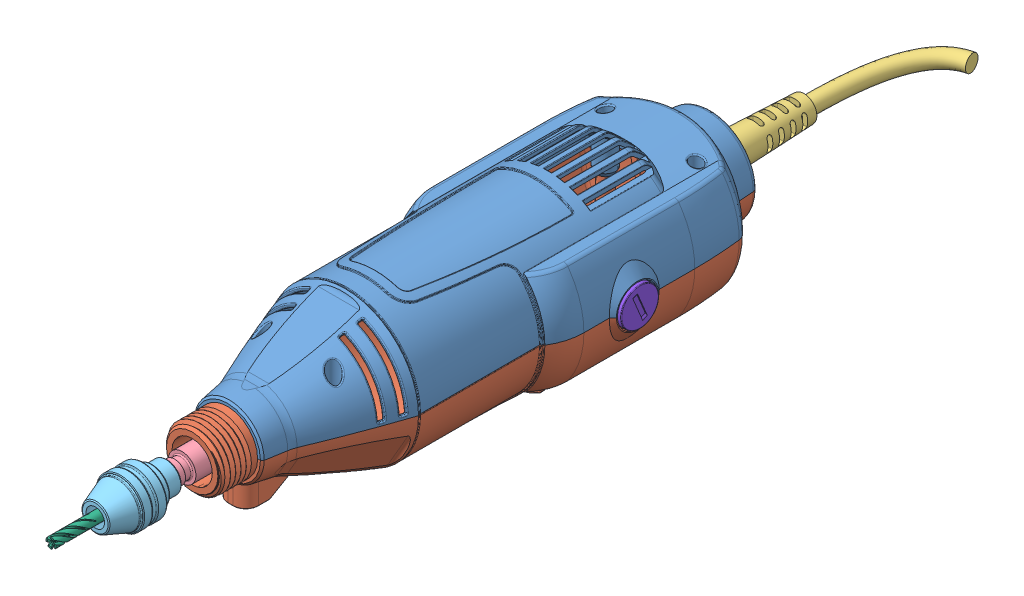
SolidWorks assembly Dremel Assembly, configuration Default. Lengths in mm.
Overall size (56.71 52.89 278.43).
9 component instances, 8 part files, 15 mates.
Components (placement in the parent):
- Dremel Left Half-1: Dremel Left Half [Default] at origin size (55.12 24.36 152.4)
- Dremel Right Half-1: Dremel Right Half [Default] x (-1 0 0) z (0 0 1) size (55.12 36.04 163.96)
- Dremel Chord-1: Dremel Chord [Default] at (0 0 -144.4625) x (1 0 0) z (0 1 0) size (22.66 78.4 16.21)
- Dremel Chuck Mount-1: Dremel Chuck Mount [Default] at (0 0 -7.9375) x (0.325874 -0.945413 0) z (-0.945413 -0.325874 0) size (8.71 38.1 8.71)
- Dremel Chuck-1: Dremel Chuck [Default] at (0 0 19.0627) x (0.99596 -0.0898 0) z (-0.0898 -0.99596 0) size (15.24 22.56 15.24)
- End Mill for Dremel-1: End Mill for Dremel [Default] at (0 0 30.1625) x (-0.564493 -0.825438 0) z (-0.825438 0.564493 0) size (5.5 25.4 5.5)
- Dremel Speed Lever-1: Dremel Speed Lever [Default] at (0 0 -93.09) x (-0.965324 -0.261055 0) z (0 0 1) size (27.22 10.71 7.94)
- Dremel Motor Adjust-1: Dremel Motor Adjust [Default] at (-22.0028 0 -101.6) x (0 0.384439 -0.92315) z (1 0 0) size (11.91 11.91 6.35)
- Dremel Motor Adjust-2: Dremel Motor Adjust [Default] at (22.0028 0 -101.6) x (0 -0.384439 0.92315) z (-1 0 0) size (11.91 11.91 6.35)
Mates (geometry in assembly coordinates):
- Coincident1: coincident anti-aligned: plane of Dremel Left Half-1 through (93.8758 0 -66.675) normal (0 -1 0); plane of Dremel Right Half-1 through (-93.8758 0 -66.675) normal (0 1 0)
- Coincident2: coincident anti-aligned: plane of Dremel Left Half-1 through (0 0 0) normal (1 0 0); plane of Dremel Right Half-1
- Coincident3: coincident aligned: plane of Dremel Left Half-1 through (0 0 0) normal (0 0 1); plane of Dremel Right Half-1 through (0 0 0) normal (0 0 1)
- Concentric1: concentric aligned: cylinder of Dremel Left Half-1 through (0 0 -152.4) axis (0 0 1) radius 6.35; cylinder of Dremel Chord-1 through (0 0 -144.4625) axis (0 0 1) radius 7.1437
- Coincident4: coincident anti-aligned: plane of Dremel Right Half-1 through (0 0 -152.4) normal (0 0 -1); plane of Dremel Chord-1 through (5.9531 0 -152.4) normal (0 0 1)
- Concentric2: concentric anti-aligned: cylinder of Dremel Right Half-1 through (0 0 -152.4) axis (0 0 1) radius 6.35; cylinder of Dremel Chuck Mount-1 through (0 0 -7.9375) axis (0 0 -1) radius 4.3561
- Distance1: distance = 19.05 mm aligned: plane of Dremel Chuck Mount-1 through (1.1381 -3.3019 30.1625) normal (0 0 1); plane of Dremel Right Half-1 through (-8.1085 0 11.1125) normal (0 0 1)
- Concentric4: concentric aligned: cylinder of Dremel Chuck Mount-1 through (0 0 -7.9375) axis (0 0 -1) radius 3.4925; cylinder of Dremel Chuck-1 through (0 0 19.0627) axis (0 0 -1) radius 3.3782
- Distance2: distance = 12.7 mm anti-aligned: plane of Dremel Right Half-1 through (-8.1085 0 11.1125) normal (0 0 1); plane of Dremel Chuck-1 through (5.7552 -0.5189 23.8125) normal (0 0 -1)
- Concentric5: concentric aligned: cone of Dremel Chuck-1 through (0 0 41.6179) axis (0 0 1); cylinder of End Mill for Dremel-1 through (0 0 55.5625) axis (0 0 1) radius 1.5875
- Coincident7: coincident anti-aligned: plane of Dremel Chuck Mount-1 through (1.1381 -3.3019 30.1625) normal (0 0 1); plane of End Mill for Dremel-1 through (0 0 30.1625) normal (0 0 -1)
- Coincident8: coincident aligned: plane of Dremel Right Half-1 through (0 0 -93.09) normal (0 0 1); plane of Dremel Speed Lever-1 through (0 0 -93.09) normal (0 0 1)
- Concentric6: concentric aligned: cylinder of Dremel Right Half-1 through (0 0 -133.35) axis (0 0 -1) radius 22.2726; cylinder of Dremel Speed Lever-1 through (0 0 -89.1213) axis (0 0 -1) radius 21.9075
- Concentric7: concentric anti-aligned: cylinder of Dremel Right Half-1 through (-25.9715 0 -101.6) axis (-1 0 0) radius 6.35; cylinder of Dremel Motor Adjust-1 through (-22.0028 0 -101.6) axis (1 0 0) radius 5.9531
- Coincident9: coincident anti-aligned: plane of Dremel Right Half-1 through (-25.9715 0 -101.6) normal (-1 0 0); plane of Dremel Motor Adjust-1 through (-25.9715 2.2886 -107.0956) normal (1 0 0)
